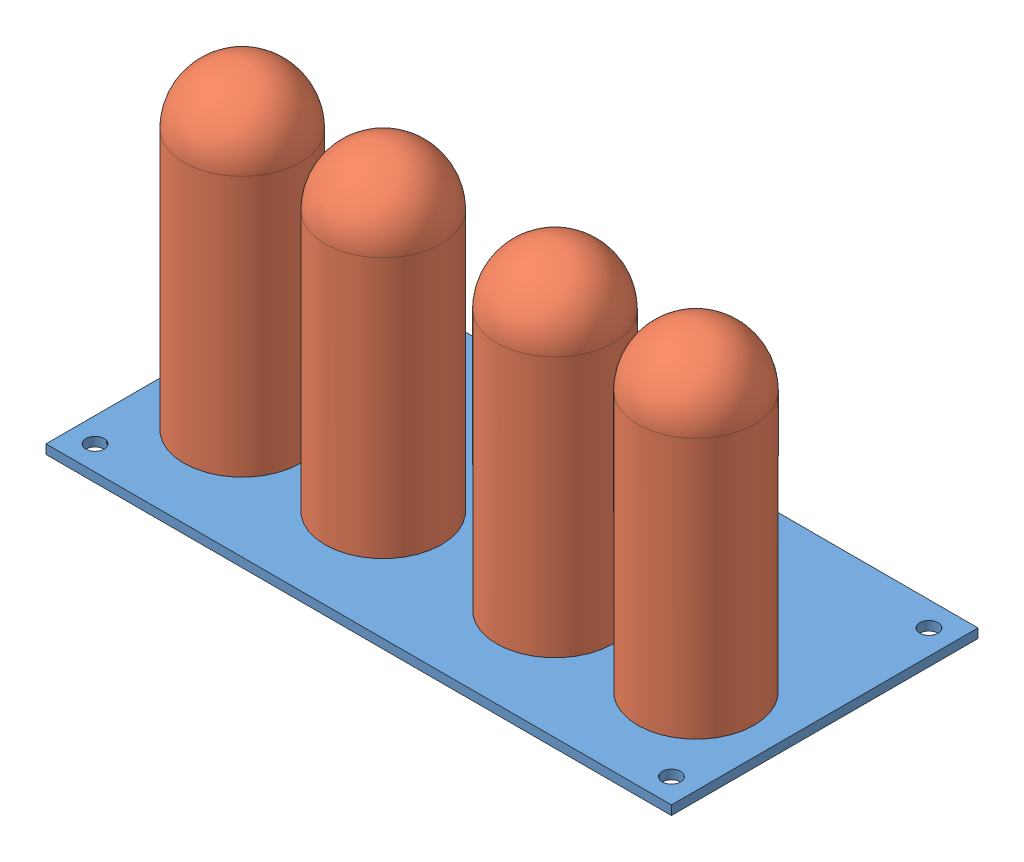
SolidWorks assembly Driver with tubes, configuration Default. Lengths in mm.
Overall size (119.32 53.5 63.05).
13 component instances, 4 part files, 31 mates.
Components (placement in the parent):
- Driver PCB-1: Driver PCB [Default] at (-32.2415 0.4018 16.2308) size (119.32 1.5 63.05)
- Nixie tube-1: Nixie tube [Default] at (-69.2415 1.9018 23.2308) size (19 52 19)
- Nixie tube-2: Nixie tube [Default] at (-46.2415 1.9018 23.2308) size (19 52 19)
- Nixie tube-3: Nixie tube [Default] at (-18.2415 1.9018 23.2308) size (19 52 19)
- Nixie tube-4: Nixie tube [Default] at (4.7585 1.9018 23.2308) size (19 52 19)
- Nixie anode-1: Nixie anode [Default] at (-69.2229 26.9018 23.5804) x (0.998589 0 -0.053108) z (0.053108 0 0.998589) size (15.76 27.56 7.8)
- Nixie anode-2: Nixie anode [Default] at (-46.2229 26.9018 23.5804) x (0.998589 0 -0.053108) z (0.053108 0 0.998589) size (15.76 27.56 7.8)
- Nixie anode-3: Nixie anode [Default] at (-18.2229 26.9018 23.5804) x (0.998589 0 -0.053108) z (0.053108 0 0.998589) size (15.76 27.56 7.8)
- Nixie anode-4: Nixie anode [Default] at (4.7771 26.9018 23.5804) x (0.998589 0 -0.053108) z (0.053108 0 0.998589) size (15.76 27.56 7.8)
- Nixie cathode 1-1: Nixie cathode 1 [Default] at (-74.3196 11.2014 25.6362) size (7.17 18.7 0.5)
- Nixie cathode 1-2: Nixie cathode 1 [Default] at (0 11.2014 25.6362) size (7.17 18.7 0.5)
- Nixie cathode 1-3: Nixie cathode 1 [Default] at (-51.442 11.2014 25.6362) size (7.17 18.7 0.5)
- Nixie cathode 1-4: Nixie cathode 1 [Default] at (-22.5302 11.2014 25.6362) size (7.17 18.7 0.5)
Mates (geometry in assembly coordinates):
- Coincident2: coincident anti-aligned: plane of Driver PCB-1 through (-32.2415 1.9018 16.2308) normal (0 1 0); circle of Nixie tube-4
- Coincident3: coincident anti-aligned: plane of Driver PCB-1 through (-32.2415 1.9018 16.2308) normal (0 1 0); circle of Nixie tube-3
- Coincident4: coincident anti-aligned: plane of Driver PCB-1 through (-32.2415 1.9018 16.2308) normal (0 1 0); circle of Nixie tube-2
- Coincident5: coincident anti-aligned: plane of Driver PCB-1 through (-32.2415 1.9018 16.2308) normal (0 1 0); circle of Nixie tube-1
- Coincident6: coincident: axis of Nixie tube-1 through (-69.2415 44.4018 23.2308) axis (0 -1 0); point of assembly
- Coincident7: coincident: axis of Nixie tube-2 through (-46.2415 44.4018 23.2308) axis (0 -1 0); point of assembly
- Coincident8: coincident: axis of Nixie tube-3 through (-18.2415 44.4018 23.2308) axis (0 -1 0); point of assembly
- Coincident9: coincident: axis of Nixie tube-4 through (4.7585 44.4018 23.2308) axis (0 -1 0); point of assembly
- Concentric1: concentric aligned: axis of Nixie tube-1 through (-69.2415 44.4018 23.2308) axis (0 -1 0); circle of Nixie anode-1
- Concentric2: concentric aligned: axis of Nixie tube-2 through (-46.2415 44.4018 23.2308) axis (0 -1 0); circle of Nixie anode-2
- Concentric3: concentric aligned: axis of Nixie tube-3 through (-18.2415 44.4018 23.2308) axis (0 -1 0); circle of Nixie anode-3
- Concentric4: concentric aligned: axis of Nixie tube-4 through (4.7585 44.4018 23.2308) axis (0 -1 0); circle of Nixie anode-4
- Distance1: distance = 15 mm anti-aligned: plane of Nixie anode-1 through (-69.3663 16.9018 20.8842) normal (0 -1 0); plane of Driver PCB-1 through (-32.2415 1.9018 16.2308) normal (0 1 0)
- Distance2: distance = 15 mm anti-aligned: plane of Nixie anode-2 through (-46.3663 16.9018 20.8842) normal (0 -1 0); plane of Driver PCB-1 through (-32.2415 1.9018 16.2308) normal (0 1 0)
- Distance5: distance = 15 mm anti-aligned: plane of Nixie anode-4 through (4.6337 16.9018 20.8842) normal (0 -1 0); plane of Driver PCB-1 through (-32.2415 1.9018 16.2308) normal (0 1 0)
- Distance6: distance = 15 mm anti-aligned: plane of Nixie anode-3 through (-18.3663 16.9018 20.8842) normal (0 -1 0); plane of Driver PCB-1 through (-32.2415 1.9018 16.2308) normal (0 1 0)
- Parallel1: parallel aligned: plane of Nixie anode-1 through (-69.5746 26.9018 23.3381) normal (-0.306419 0 -0.951897); plane of Nixie anode-2 through (-46.5746 26.9018 23.3381) normal (-0.306419 0 -0.951897)
- Parallel2: parallel aligned: plane of Nixie anode-2 through (-46.5746 26.9018 23.3381) normal (-0.306419 0 -0.951897); plane of Nixie anode-3 through (-18.5746 26.9018 23.3381) normal (-0.306419 0 -0.951897)
- Parallel3: parallel aligned: plane of Nixie anode-3 through (-18.5746 26.9018 23.3381) normal (-0.306419 0 -0.951897); plane of Nixie anode-4 through (4.4254 26.9018 23.3381) normal (-0.306419 0 -0.951897)
- Distance7: distance = 16 mm anti-aligned: plane of Nixie cathode 1-1 through (-67.6514 17.9018 26.1362) normal (0 -1 0); plane of Driver PCB-1 through (-32.2415 1.9018 16.2308) normal (0 1 0)
- Parallel4: parallel aligned: plane of Driver PCB-1 through (-83.2415 1.9018 41.2308) normal (0 0 1); plane of Nixie cathode 1-1 through (-74.3196 11.2014 26.1362) normal (0 0 1)
- Coincident25: coincident: line of Nixie anode-1 through (-76.7139 16.9018 25.6362) axis (0 1 0); plane of Nixie cathode 1-1 through (-74.3196 11.2014 25.6362) normal (0 0 -1)
- Distance8: distance = 16 mm anti-aligned: plane of Nixie cathode 1-2 through (6.6682 17.9018 26.1362) normal (0 -1 0); plane of Driver PCB-1 through (-32.2415 1.9018 16.2308) normal (0 1 0)
- Parallel5: parallel aligned: plane of Driver PCB-1 through (-83.2415 1.9018 41.2308) normal (0 0 1); plane of Nixie cathode 1-2 through (0 11.2014 26.1362) normal (0 0 1)
- Coincident26: coincident: line of Nixie anode-2 through (-53.7139 16.9018 25.6362) axis (0 1 0); plane of Nixie cathode 1-2 through (0 11.2014 25.6362) normal (0 0 -1)
- Distance9: distance = 16 mm anti-aligned: plane of Nixie cathode 1-3 through (-44.7738 17.9018 26.1362) normal (0 -1 0); plane of Driver PCB-1 through (-32.2415 1.9018 16.2308) normal (0 1 0)
- Parallel6: parallel aligned: plane of Driver PCB-1 through (-83.2415 1.9018 41.2308) normal (0 0 1); plane of Nixie cathode 1-3 through (-51.442 11.2014 26.1362) normal (0 0 1)
- Coincident27: coincident: line of Nixie anode-3 through (-25.7139 16.9018 25.6362) axis (0 1 0); plane of Nixie cathode 1-3 through (-51.442 11.2014 25.6362) normal (0 0 -1)
- Distance10: distance = 16 mm anti-aligned: plane of Nixie cathode 1-4 through (-15.862 17.9018 26.1362) normal (0 -1 0); plane of Driver PCB-1 through (-32.2415 1.9018 16.2308) normal (0 1 0)
- Parallel7: parallel aligned: plane of Driver PCB-1 through (-83.2415 1.9018 41.2308) normal (0 0 1); plane of Nixie cathode 1-4 through (-22.5302 11.2014 26.1362) normal (0 0 1)
- Coincident28: coincident: line of Nixie anode-2 through (-53.7139 16.9018 25.6362) axis (0 1 0); plane of Nixie cathode 1-4 through (-22.5302 11.2014 25.6362) normal (0 0 -1)
